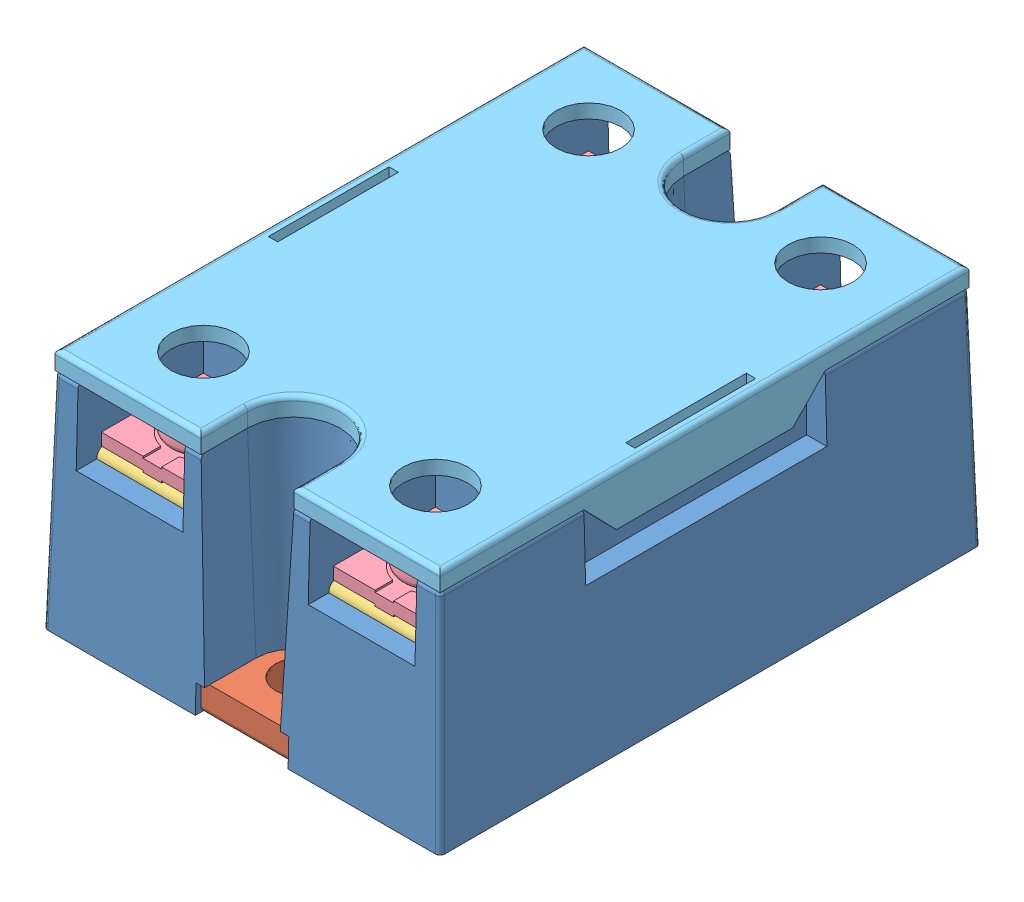
SolidWorks assembly SSR-25 Relay, configuration Default. Lengths in mm.
Overall size (42.76 26 58.26).
11 component instances, 5 part files, 15 mates.
Components (placement in the parent):
- SE1206.Uxcell.SSR-25.B01.SSR.Body-1: SE1206.Uxcell.SSR-25.B01.SSR.Body [Default] at origin size (42.76 24 58.26)
- SE1206.Uxcell.SSR-25.B02.Metal.Back.Cover-1: SE1206.Uxcell.SSR-25.B02.Metal.Back.Cover [Default] at origin size (38.5 3 57)
- SE1206.Uxcell.SSR-25.B03.Metal.Contact-1: SE1206.Uxcell.SSR-25.B03.Metal.Contact [Default] at (-12.5 15 20.75) size (11.5 2 11.5)
- SE1206.Uxcell.SSR-25.B03.Metal.Contact-2: SE1206.Uxcell.SSR-25.B03.Metal.Contact [Default] at (12.5 15 20.75) size (11.5 2 11.5)
- SE1206.Uxcell.SSR-25.B03.Metal.Contact-3: SE1206.Uxcell.SSR-25.B03.Metal.Contact [Default] at (-12.5 15 -20.75) x (-1 0 0) z (0 0 -1) size (11.5 2 11.5)
- SE1206.Uxcell.SSR-25.B03.Metal.Contact-4: SE1206.Uxcell.SSR-25.B03.Metal.Contact [Default] at (12.5 15 -20.75) x (-1 0 0) z (0 0 -1) size (11.5 2 11.5)
- SE1206.Uxcell.SSR-25.B04.Contact.Bolt-1: SE1206.Uxcell.SSR-25.B04.Contact.Bolt [Default] at (-12.5 18.5 20.75) size (11 12.09 11)
- SE1206.Uxcell.SSR-25.B04.Contact.Bolt-2: SE1206.Uxcell.SSR-25.B04.Contact.Bolt [Default] at (12.5 18.5 20.75) x (-1 0 0) z (0 0 -1) size (11 12.09 11)
- SE1206.Uxcell.SSR-25.B04.Contact.Bolt-3: SE1206.Uxcell.SSR-25.B04.Contact.Bolt [Default] at (-12.5 18.5 -20.75) size (11 12.09 11)
- SE1206.Uxcell.SSR-25.B04.Contact.Bolt-4: SE1206.Uxcell.SSR-25.B04.Contact.Bolt [Default] at (12.5 18.5 -20.75) x (-1 0 0) z (0 0 -1) size (11 12.09 11)
- SE1206.Uxcell.SSR-25.B05.Clear.Front.Cover-3: SE1206.Uxcell.SSR-25.B05.Clear.Front.Cover [Default] at (0 24 0) size (41.5 5.6 57)
Mates (geometry in assembly coordinates):
- Coincident1: coincident: plane of SE1206.Uxcell.SSR-25.B01.SSR.Body-1 through (0 0 0) normal (0 0 1); plane of assembly through (0 0 0) normal (0 0 1)
- Coincident2: coincident: plane of SE1206.Uxcell.SSR-25.B01.SSR.Body-1 through (0 0 0) normal (1 0 0); plane of assembly through (0 0 0) normal (1 0 0)
- Coincident3: coincident: plane of SE1206.Uxcell.SSR-25.B01.SSR.Body-1 through (0 0 0) normal (0 1 0); plane of assembly through (0 0 0) normal (0 1 0)
- Coincident4: coincident: plane of SE1206.Uxcell.SSR-25.B01.SSR.Body-1 through (0 3 0) normal (0 -1 0); plane of SE1206.Uxcell.SSR-25.B02.Metal.Back.Cover-1 through (0 3 0) normal (0 1 0)
- Coincident5: coincident: plane of SE1206.Uxcell.SSR-25.B01.SSR.Body-1 through (19.25 3 27) normal (-1 0 0); plane of SE1206.Uxcell.SSR-25.B02.Metal.Back.Cover-1 through (19.25 3 -27) normal (1 0 0)
- Coincident6: coincident: plane of SE1206.Uxcell.SSR-25.B01.SSR.Body-1 through (-19.25 3 -27) normal (0 0 1); plane of SE1206.Uxcell.SSR-25.B02.Metal.Back.Cover-1 through (5 3 -27) normal (0 0 -1)
- Coincident7: coincident: plane of SE1206.Uxcell.SSR-25.B01.SSR.Body-1 through (-6.75 16 28.5) normal (-1 0 0); plane of SE1206.Uxcell.SSR-25.B03.Metal.Contact-1 through (-6.75 17 15) normal (1 0 0)
- Coincident8: coincident: plane of SE1206.Uxcell.SSR-25.B01.SSR.Body-1 through (-18.25 16 15) normal (0 0 1); plane of SE1206.Uxcell.SSR-25.B03.Metal.Contact-1 through (-18.25 17 15) normal (0 0 -1)
- Coincident9: coincident: line of SE1206.Uxcell.SSR-25.B01.SSR.Body-1 through (-18.25 16 26.5) axis (1 0 0); line of SE1206.Uxcell.SSR-25.B03.Metal.Contact-1 through (-6.75 16 26.5) axis (-1 0 0)
- Concentric1: concentric: cylinder of SE1206.Uxcell.SSR-25.B03.Metal.Contact-1 through (-12.5 15 20.75) axis (0 1 0) radius 2; cylinder of SE1206.Uxcell.SSR-25.B04.Contact.Bolt-1 through (-12.5 9.5 20.75) axis (0 1 0) radius 2
- Coincident10: coincident: plane of SE1206.Uxcell.SSR-25.B03.Metal.Contact-1 through (-12.5 17 20.75) normal (0 1 0); plane of SE1206.Uxcell.SSR-25.B04.Contact.Bolt-1 through (-12.5 17 20.75) normal (0 -1 0)
- Coincident11: coincident: plane of SE1206.Uxcell.SSR-25.B04.Contact.Bolt-1 through (-13.25 20.1 25.75) normal (1 0 0); plane of SE1206.Uxcell.SSR-25.B04.Contact.Bolt-3 through (-13.25 20.1 -15.75) normal (1 0 0)
- Coincident12: coincident: plane of SE1206.Uxcell.SSR-25.B01.SSR.Body-1 through (0 24 0) normal (0 1 0); plane of SE1206.Uxcell.SSR-25.B05.Clear.Front.Cover-3 through (0 24 0) normal (0 -1 0)
- Coincident13: coincident: plane of SE1206.Uxcell.SSR-25.B01.SSR.Body-1 through (-19.75 0 0) normal (-1 0 0); plane of SE1206.Uxcell.SSR-25.B05.Clear.Front.Cover-3 through (-19.75 24 0) normal (1 0 0)
- Coincident14: coincident: plane of SE1206.Uxcell.SSR-25.B01.SSR.Body-1 through (19.75 24 6.5) normal (0 0 1); plane of SE1206.Uxcell.SSR-25.B05.Clear.Front.Cover-3 through (19.45 20.4 6.5) normal (0 0 1)
